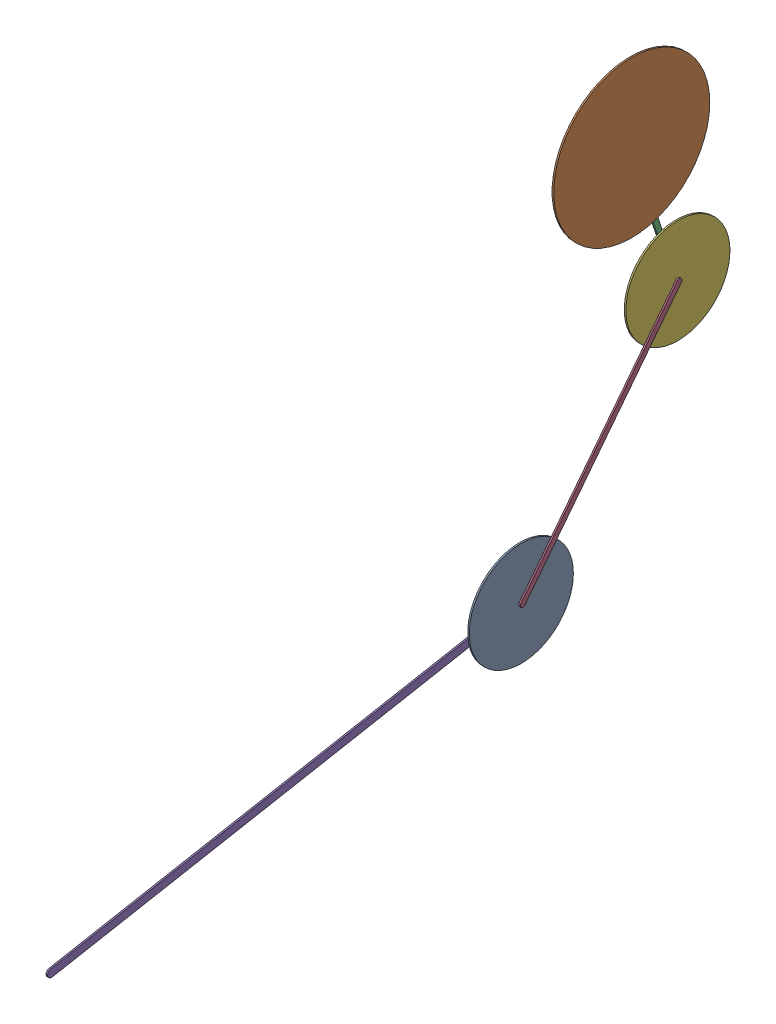
SolidWorks assembly percy, configuration Default. Lengths in mm.
Overall size (9 976.55 1338.51).
6 component instances, 5 part files, 10 mates.
Components (placement in the parent):
- circle_200-1: circle_200 [Default] at (0 -652.336 212.1182) size (3 200 200)
- head'-1: head' [Default] at origin size (3 300 300)
- line_280-1: line_280 [Default] at (-3 0 0) x (1 0 0) z (0 -0.3169 0.948459) size (3 290 10)
- line_490-1: line_490 [Default] at (3 -265.5685 -88.7321) x (1 0 0) z (0 0.61398 0.789321) size (3 500 10)
- line_915-1: line_915 [Default] at (-3 -652.336 212.1182) x (1 0 0) z (0 -0.007976 0.999968) size (3 174.47 916)
- circle_200-2: circle_200 [Default] at (0 -265.5685 -88.7321) x (1 0 0) z (0 0.933994 0.357289) size (3 200 200)
Mates (geometry in assembly coordinates):
- Coincident1: coordinate: point of head'-1
- Coincident2: coincident anti-aligned: plane of head'-1 through (0 0 0) normal (-1 0 0); plane of line_280-1 through (0 0 0) normal (1 0 0)
- Concentric1: concentric aligned: circle of head'-1; circle of line_280-1
- Coincident3: coincident anti-aligned: plane of line_280-1 through (0 0 0) normal (1 0 0); plane of circle_200-2 through (0 -265.5685 -88.7321) normal (-1 0 0)
- Concentric2: concentric aligned: circle of line_280-1; circle of circle_200-2
- Coincident4: coincident anti-aligned: plane of line_490-1 through (3 -652.336 212.1182) normal (-1 0 0); plane of circle_200-2 through (3 -265.5685 -88.7321) normal (1 0 0)
- Concentric3: concentric aligned: circle of line_490-1; circle of circle_200-2
- Concentric4: concentric aligned: circle of circle_200-1; circle of line_490-1
- Coincident6: coincident anti-aligned: plane of circle_200-1 through (0 -652.336 212.1182) normal (-1 0 0); plane of line_915-1 through (0 -652.336 212.1182) normal (1 0 0)
- Concentric5: concentric aligned: circle of circle_200-1; circle of line_915-1
